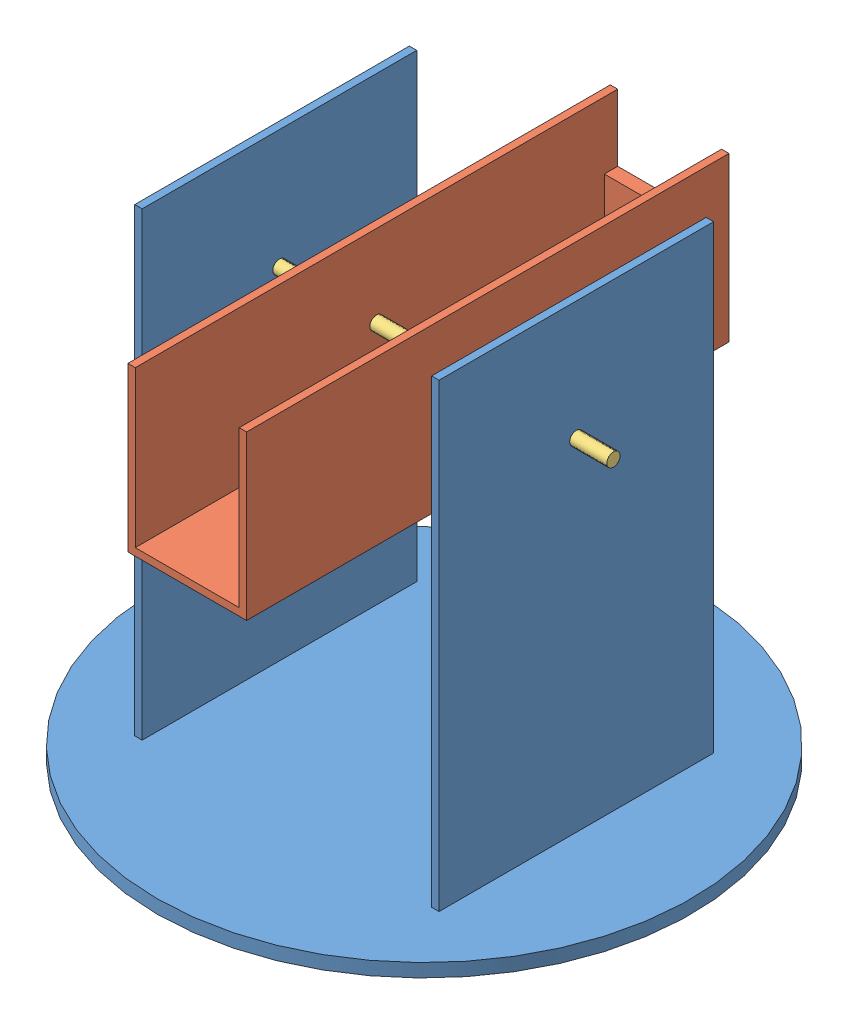
SolidWorks assembly Assem1, configuration Default. Lengths in mm.
Overall size (360 319 360).
3 component instances, 3 part files, 2 mates.
Components (placement in the parent):
- PART 2-1: PART 2 [Default] at (73.6872 62.4635 291.307) size (360 319 360)
- Part3-1: Part3 [Default] at (122.053 242.4635 291.307) x (0 0 -1) z (1 0 0) size (325 110 80)
- rod-1: rod [Default] at (-28.8128 294.7212 292.3021) x (0 1 0) z (0 0 1) size (9 230 9)
Mates (geometry in assembly coordinates):
- Concentric1: concentric anti-aligned: circle of PART 2-1; circle of Part3-1
- Coincident10: coincident aligned: circle of PART 2-1; circle of rod-1
